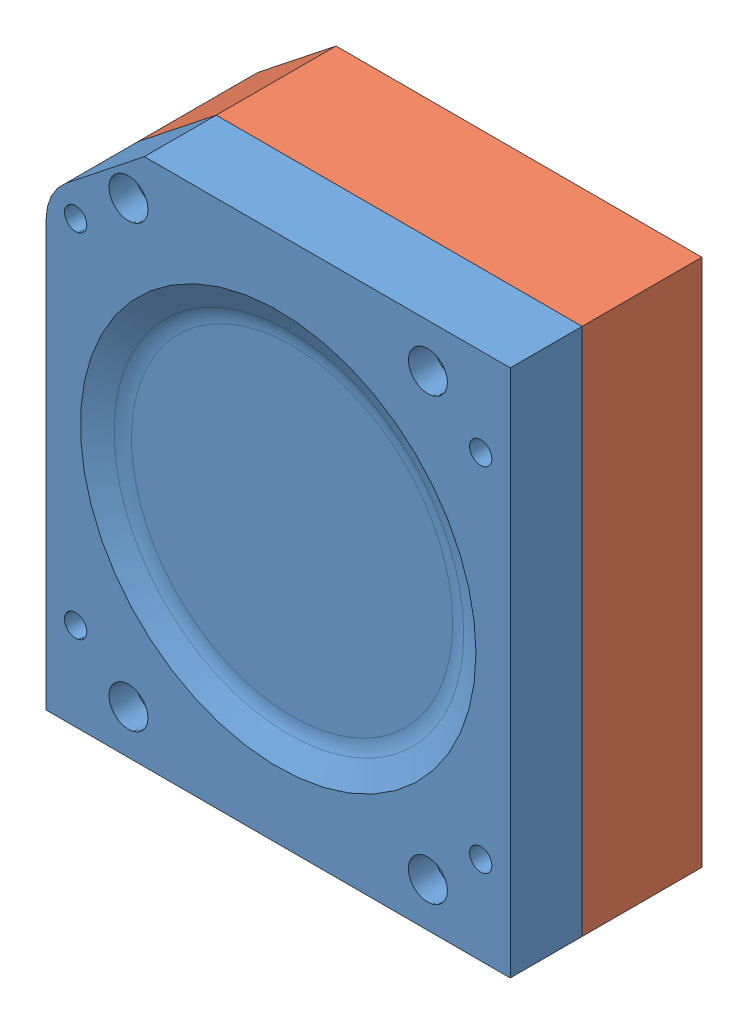
SolidWorks assembly Assem1, configuration Default. Lengths in mm.
Overall size (263.53 300 108.8).
2 component instances, 2 part files, 4 mates.
Components (placement in the parent):
- P_MOLD_SECTION_2-1: P_MOLD_SECTION_2 [Default] at (263.525 0 -191.3527) x (0 1 0) z (0 0 1) size (300 263.53 40.81)
- P_MOLD_SECTION_3-1: P_MOLD_SECTION_3 [Default] at (263.525 0 -191.3527) x (0 1 0) z (0 0 1) size (300 263.53 67.99)
Mates (geometry in assembly coordinates):
- Coincident1: coincident: point of ?
- Coincident2: coincident: plane of P_MOLD_SECTION_2-1 through (263.525 0 -40.8104) normal (0 0 -1); plane of P_MOLD_SECTION_3-1 through (263.525 0 -40.8104) normal (0 0 1)
- Coincident3: coincident: plane of P_MOLD_SECTION_2-1 through (0 0 -191.3527) normal (-1 0 0); plane of P_MOLD_SECTION_3-1 through (0 0 -191.3527) normal (-1 0 0)
- Coincident4: coincident: plane of P_MOLD_SECTION_2-1 through (0 0 95.4128) normal (0 -1 0); plane of P_MOLD_SECTION_3-1 through (0 0 95.4128) normal (0 -1 0)
